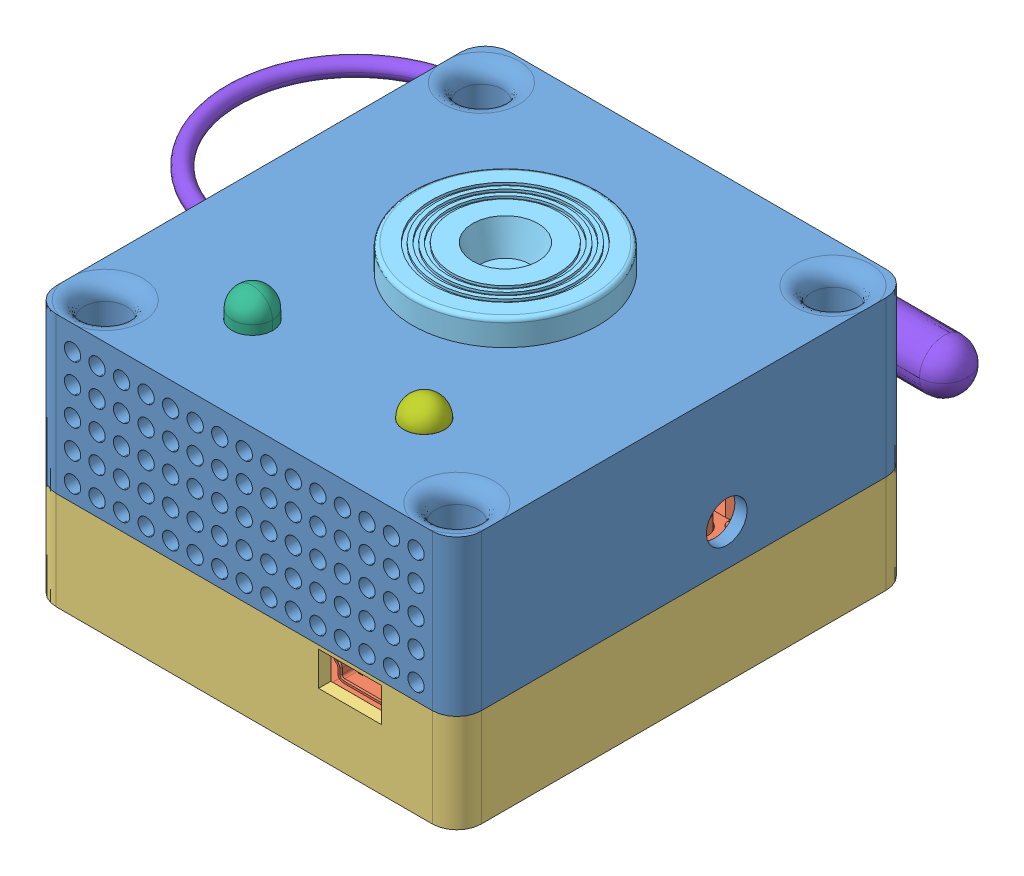
SolidWorks assembly Assem1, configuration Default. Lengths in mm.
Overall size (76.5 34.53 66).
8 component instances, 8 part files, 18 mates.
Components (placement in the parent):
- Upper part-1: Upper part [Default] at (124.5105 60.696 -21.1702) x (-1 0 0) z (0 0 1) size (52 19 55.5)
- ChefAlarmPCB-1: ChefAlarmPCB [Default] at (194.1305 37.1075 -149.6702) x (-1 0 0) z (0 1 0) size (48.78 52.08 24.33)
- lower part-1: lower part [Default] at (72.5105 29.696 -21.1702) size (52 12 55.5)
- li ion cell-1: li ion cell [Default] at (81.5105 31.196 -22.6702) size (34 5.2 50)
- Beeper buzzer 3-24V 23dia 11h leaded.step-1: Beeper buzzer 3-24V 23dia 11h leaded.step [Default] at (98.5105 52.926 -53.1002) x (0 0 -1) z (0 1 0) size (34.56 22.7 11.72)
- LED green.step-1: LED green.step [Default] at (88.0105 30.3261 -32.6702) size (5.52 33.9 5.87)
- red-led-5mm-1: red-led-5mm [Default] at (109.0105 55.051 -32.6702) x (1 0 0) z (0 1 0) size (5.95 5.62 28.7)
- ds18b20.step-1: ds18b20.step [Default] at (98.9575 46.696 -84.1702) x (0 0 1) z (1 0 0) size (34.1 6 75.95)
Mates (geometry in assembly coordinates):
- Coincident10: coincident anti-aligned: plane of newPCB-1 through (74.2425 36.696 -22.6702) normal (0 0 1); plane of lower part-1 through (74.0105 31.196 -22.6702) normal (0 0 -1)
- Coincident11: coincident anti-aligned: plane of newPCB-1 through (123.0105 36.696 -22.6702) normal (1 0 0); plane of lower part-1 through (123.0105 31.196 -75.1702) normal (-1 0 0)
- Coincident12: coincident anti-aligned: plane of newPCB-1 through (123.0105 36.696 -74.7402) normal (0 -1 0); plane of lower part-1 through (77.0105 36.696 -25.6702) normal (0 1 0)
- Coincident13: coincident anti-aligned: plane of lower part-1 through (72.5105 31.196 -21.1702) normal (0 1 0); plane of li ion cell-1 through (81.5105 31.196 -22.6702) normal (0 -1 0)
- Parallel1: parallel aligned: line of lower part-1 through (74.0105 41.696 -75.1702) axis (0 0 1); line of li ion cell-1 through (81.5105 36.396 -72.6702) axis (0 0 1)
- Parallel2: parallel aligned: line of lower part-1 through (74.0105 41.696 -22.6702) axis (1 0 0); line of li ion cell-1 through (81.5105 36.396 -22.6702) axis (1 0 0)
- Coincident16: coincident anti-aligned: plane of lower part-1 through (81.5105 31.196 -22.6702) normal (1 0 0); plane of li ion cell-1 through (81.5105 36.396 -22.6702) normal (-1 0 0)
- Coincident17: coincident anti-aligned: plane of lower part-1 through (74.0105 31.196 -22.6702) normal (0 0 -1); plane of li ion cell-1 through (81.5105 36.396 -22.6702) normal (0 0 1)
- Concentric1: concentric anti-aligned: cylinder of Upper part-1 through (98.5105 60.696 -53.1002) axis (0 -1 0) radius 11.35; cylinder of Beeper buzzer 3-24V 23dia 11h leaded.step-1 through (98.5105 52.926 -53.1002) axis (0 1 0) radius 11.35
- Coincident19: coincident anti-aligned: plane of Upper part-1 through (98.5105 54.196 -68.5502) normal (0 -1 0); plane of Beeper buzzer 3-24V 23dia 11h leaded.step-1 through (98.5105 54.196 -67.1271) normal (0 1 0)
- Concentric2: concentric aligned: circle of Upper part-1; circle of LED green.step-1
- Concentric3: concentric aligned: circle of Upper part-1; circle of red-led-5mm-1
- Distance1: distance = 3.57 mm aligned: plane of LED green.step-1 through (88.0105 55.626 -32.6702) normal (0 -1 0); plane of Upper part-1 through (124.5105 59.196 -21.1702) normal (0 -1 0)
- Distance2: distance = 3.57 mm anti-aligned: plane of red-led-5mm-1 through (109.0105 55.626 -32.6702) normal (0 1 0); plane of Upper part-1 through (124.5105 59.196 -21.1702) normal (0 -1 0)
- Coincident24: coincident anti-aligned: plane of Upper part-1 through (124.5105 41.696 -21.1702) normal (0 -1 0); plane of lower part-1 through (72.5105 41.696 -21.1702) normal (0 1 0)
- Coincident25: coincident anti-aligned: line of Upper part-1 through (124.5105 41.696 -73.6702) axis (0 0 1); line of lower part-1 through (124.5105 41.696 -24.1702) axis (0 0 -1)
- Coincident26: coincident anti-aligned: line of Upper part-1 through (75.5105 41.696 -76.6702) axis (1 0 0); line of lower part-1 through (121.5105 41.696 -76.6702) axis (-1 0 0)
- Concentric6: concentric anti-aligned: circle of Upper part-1; cylinder of ds18b20.step-1 through (73.9575 46.696 -54.1702) axis (-1 0 0) radius 1
